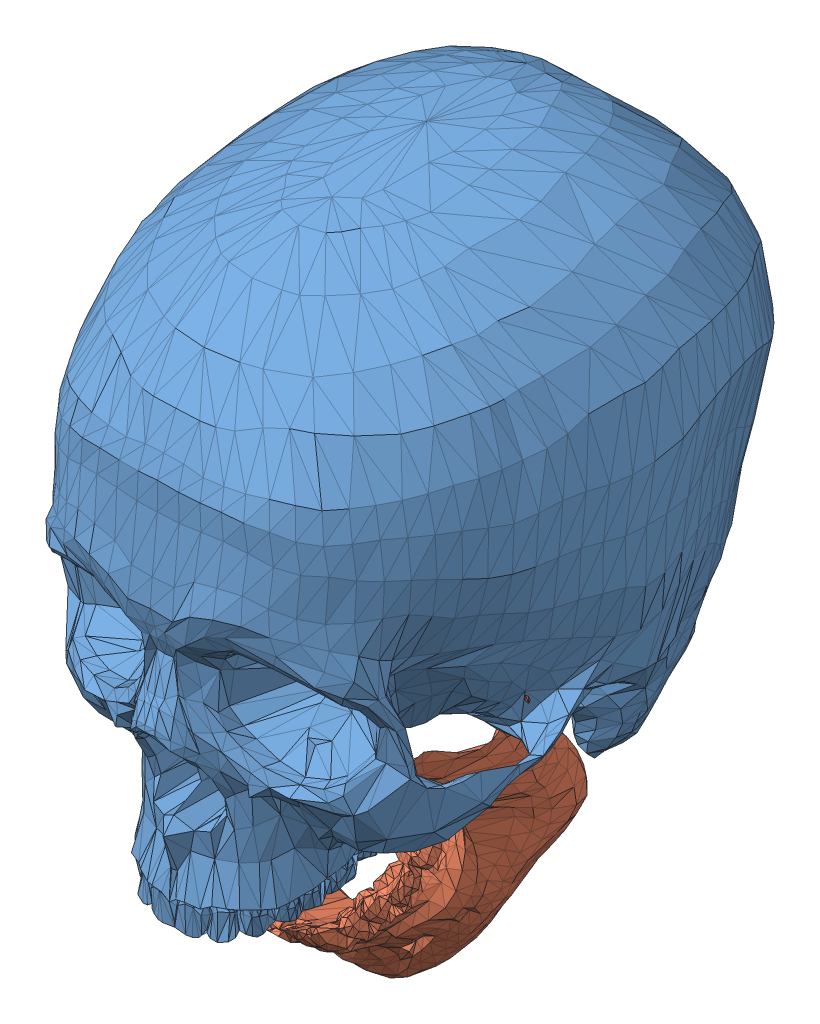
SolidWorks assembly SKULL, configuration Default. Lengths in mm.
Overall size (172.21 211.27 198.72).
2 component instances, 2 part files, 2 mates.
Components (placement in the parent):
- skull-1: skull [Default] at (0.7678 -95.2277 74.9704) x (0.962066 -0.010996 0.272596) z (-0.013186 0.996145 0.08672) size (132.77 155.87 151.97)
- skull quijada-1: skull quijada [Default] at (1.4169 -86.7543 37.7852) x (0.962066 -0.135924 0.236546) z (-0.02567 0.818101 0.574501) size (92.85 77 82.28)
Mates (geometry in assembly coordinates):
- Concentric5: concentric aligned: circle of skull-1; circle of skull quijada-1
- Coincident7: coincident aligned: plane of skull-1; plane of skull quijada-1
